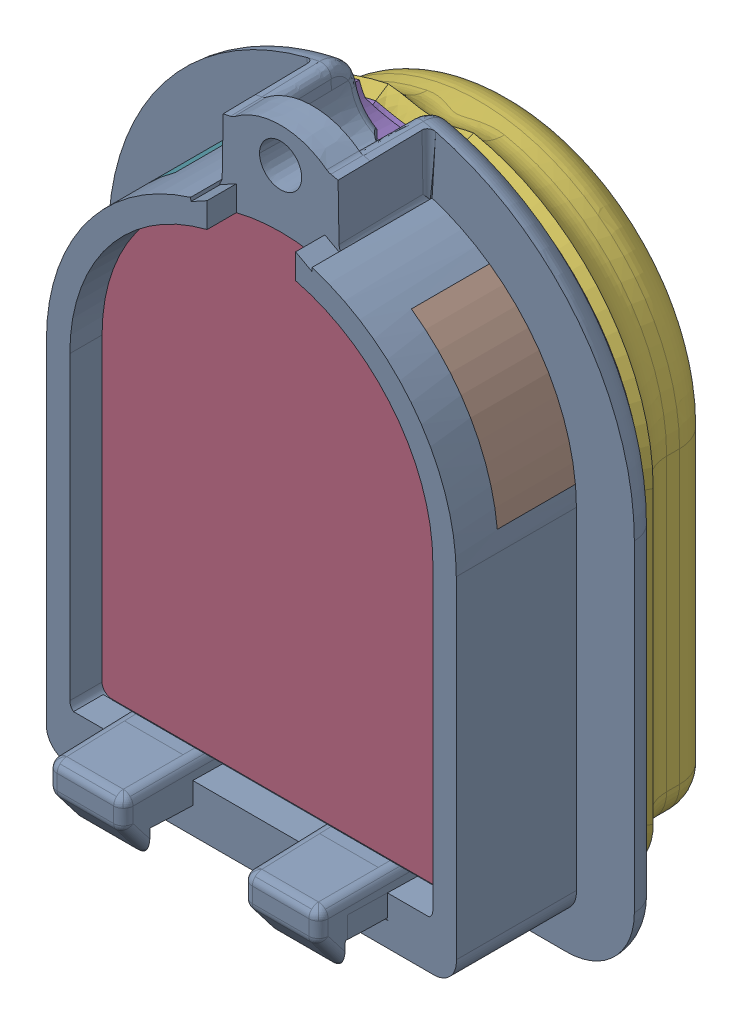
SolidWorks assembly tipandlense, configuration 默认. Lengths in mm.
Overall size (26.95 34.26 17.16).
7 component instances, 6 part files, 18 mates.
Components (placement in the parent):
- Tip1-1: Tip1 [默认] at (-1.9035 7.7463 -5.5591) size (26.95 34.26 11.2)
- lensnew-1: lensnew [默认] at (-1.9035 7.7463 -5.5591) size (18.6 25.2 6)
- Skin0.2-1: Skin0.2 [默认] at (-1.9035 7.4963 -5.5591) x (-1 0 0) z (0 0 -1) size (23.9 30.06 5.2)
- Skin1-1: Skin1 [默认] at (-1.9035 7.4963 -5.5591) x (-1 0 0) z (0 0 -1) size (22.77 29.32 5.25)
- sidelens1-1: sidelens1 [默认] at (-1.9035 7.7463 -6.2091) size (6.4 7.71 4)
- sidelens1-2: sidelens1 [默认] at (-1.9035 7.7463 2.0909) x (-1 0 0) z (0 0 -1) size (6.4 7.71 4)
- bottomlens-1: bottomlens [默认] at (-5.9035 -10.5037 0.4409) x (1 0 0) z (0 1 0) size (8 4.5 2.35)
Mates (geometry in assembly coordinates):
- 同心1: concentric aligned: cylinder of Tip1-1 through (-1.9035 7.7463 51.2878) axis (0 0 -1) radius 9.3; cylinder of lensnew-1 through (-1.9035 7.7463 0.4409) axis (0 0 -1) radius 9.3
- 重合1: coincident anti-aligned: plane of Tip1-1 through (-1.9035 -8.1537 51.2878) normal (0 1 0); plane of lensnew-1 through (-11.2035 -8.1537 0.4409) normal (0 -1 0)
- 重合2: coincident aligned: plane of Tip1-1 through (-1.964 4.3089 -5.5591) normal (0 0 -1); plane of lensnew-1 through (-1.9035 7.7463 -5.5591) normal (0 0 -1)
- 重合3: coincident anti-aligned: plane of lensnew-1 through (-1.9035 7.7463 -5.5591) normal (0 0 -1); plane of Skin0.2-1 through (-1.9035 7.4963 -5.5591) normal (0 0 1)
- 同心2: concentric aligned: cone of Tip1-1 through (-1.9035 19.9963 -1.0591) axis (0 0 1); cylinder of Skin0.2-1 through (-1.9035 19.9963 -6.3091) axis (0 0 1) radius 2.75
- 宽度1: width aligned: plane of Skin0.2-1 through (-13.8535 7.4963 -5.5591) normal (-1 0 0); plane of Skin0.2-1 through (10.0465 7.4963 -5.5591) normal (1 0 0); plane of Tip1-1 through (-12.4035 7.7463 2.0909) normal (-1 0 0); plane of Tip1-1 through (8.5965 7.7463 2.0909) normal (1 0 0)
- 重合4: coincident anti-aligned: plane of Skin0.2-1 through (-1.9035 7.4963 -10.7591) normal (0 0 -1); plane of Skin1-1 through (-1.9035 7.4963 -10.7591) normal (0 0 1)
- 宽度2: width anti-aligned: plane of Skin0.2-1 through (-13.8535 7.4963 -5.5591) normal (-1 0 0); plane of Skin0.2-1 through (10.0465 7.4963 -5.5591) normal (1 0 0); plane of Skin1-1 through (-12.8325 0.0508 -6.2245) normal (-0.891007 0 0.45399); plane of Skin1-1 through (9.0255 0.0508 -6.2245) normal (0.891007 0 0.45399)
- 重合5: coincident aligned: cone of Skin0.2-1 through (-1.9035 7.4963 -6.2245) axis (0 0 1); cone of Skin1-1 through (-1.9035 7.4963 -6.2245) axis (0 0 1)
- 重合6: coincident: plane of Tip1-1 through (-16.7251 9.2061 -4.0591) normal (0.104528 0.994522 0); plane of sidelens1-1 through (8.4147 6.5638 -0.0591) normal (-0.104528 -0.994522 0)
- 重合7: coincident: plane of Tip1-1 through (-1.9035 7.7463 -4.0591) normal (0 0 1); plane of sidelens1-1 through (8.4147 6.5638 -4.0591) normal (0 0 -1)
- 同心3: concentric aligned: cylinder of Tip1-1 through (-1.9035 7.7463 2.0909) axis (0 0 -1) radius 10.5; cylinder of sidelens1-1 through (-1.9035 7.7463 -0.0591) axis (0 0 -1) radius 10.5
- 同心4: concentric: cylinder of Tip1-1 through (-1.9035 7.7463 2.0909) axis (0 0 -1) radius 10.5; cylinder of sidelens1-2 through (-1.9035 7.7463 -4.0591) axis (0 0 1) radius 10.5
- 重合8: coincident: plane of Tip1-1 through (12.0819 17.1622 -0.0591) normal (0.104528 -0.994522 0); plane of sidelens1-2 through (-13.0579 14.5199 -4.0591) normal (-0.104528 0.994522 0)
- 重合9: coincident anti-aligned: plane of Tip1-1 through (-1.9035 7.7463 -4.0591) normal (0 0 1); plane of sidelens1-2 through (-1.9035 7.7463 -4.0591) normal (0 0 -1)
- 重合10: coincident: plane of lensnew-1 through (-11.2035 -8.1537 0.4409) normal (0 -1 0); plane of bottomlens-1 through (-6.7675 -8.1537 0.4409) normal (0 1 0)
- 重合11: coincident: plane of Tip1-1 through (-5.9035 -18.1537 0.4409) normal (0 0 -1); plane of bottomlens-1 through (-6.7675 -8.1537 0.4409) normal (0 0 1)
- 重合12: coincident anti-aligned: plane of Tip1-1 through (2.0965 -18.1537 0.4409) normal (-1 0 0); plane of bottomlens-1 through (1.2325 -8.1537 0.4409) normal (1 0 0)
